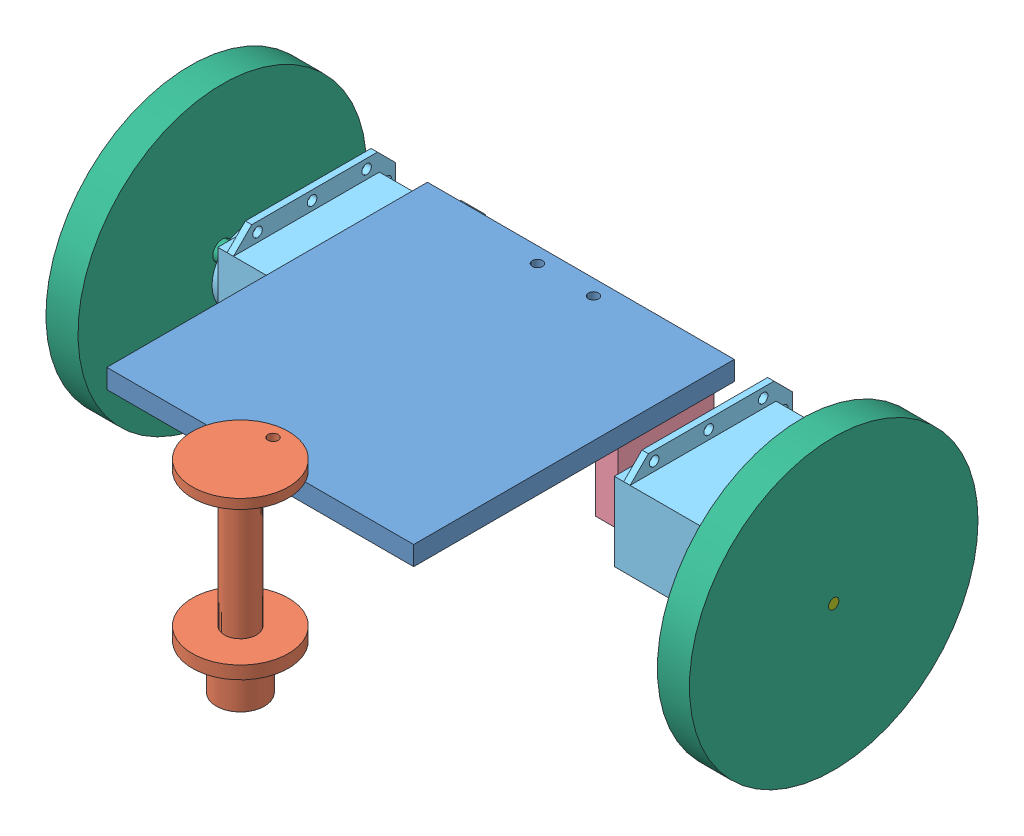
SolidWorks assembly Assem1, configuration Default. Lengths in mm.
Overall size (200.68 111.99 157.99).
10 component instances, 7 part files, 27 mates.
Components (placement in the parent):
- base plate-1: base plate [Default] at origin size (95.7 6 100)
- castor-1: castor [Default] at (0.7825 -41 56.9721) x (-0.997467 0 0.071136) z (-0.071136 0 -0.997467) size (30 63 30)
- castorwheel-1: castorwheel [Default] at (0.7825 -54 56.9721) x (-0.599803 0 0.800148) z (0 1 0) size (13 13 17.5)
- motor clamp-2: motor clamp [Default] x (-1 0 0) z (0 0 1) size (84.11 28 30)
- MX-28-1: MX-28 [Default] at (227.8585 63.0507 -670.7152) x (-1 0 0) z (0 0 1) size (43.48 35.8 50.6)
- MX-28-2: MX-28 [Default] at (-228.8539 -116.0004 -670.7152) size (43.48 35.8 50.6)
- wheel-1: wheel [Default] at (-95.84 -26.3818 -29.0254) x (0 0.286108 0.958197) z (0 -0.958197 0.286108) size (90 14.8 90)
- shaft-1: shaft [Default] at (-93.44 -26.4668 -29) x (0 -1 0) z (0 0 1) size (3.2 16.6 3.2)
- wheel-2: wheel [Default] at (94.8445 -26.4828 -29.0887) x (0 -1 0) z (0 0 1) size (90 14.8 90)
- shaft-2: shaft [Default] at (92.4445 -26.4828 -29) x (0 1 0) z (0 0 1) size (3.2 16.6 3.2)
Mates (geometry in assembly coordinates):
- Coincident3: coincident: plane of base plate-1 through (0 0 0) normal (0 0 1); plane of assembly through (0 0 0) normal (0 0 1)
- Coincident4: coincident: plane of base plate-1 through (0 0 0) normal (0 1 0); plane of assembly through (0 0 0) normal (0 1 0)
- Coincident6: coincident aligned: plane of base plate-1 through (0 0 0) normal (1 0 0); plane of assembly through (0 0 0) normal (1 0 0)
- Coincident7: coincident anti-aligned: plane of base plate-1 through (0 3 0) normal (0 1 0); plane of base plate-1 through (47.85 3 -64) normal (0 -1 0)
- Coincident8: coincident aligned: axis of base plate-1 through (8.75 3 -45.1814) axis (0 -1 0); axis of base plate-1 through (8.75 8 -45.1814) axis (0 -1 0)
- Coincident9: coincident anti-aligned: axis of base plate-1 through (0 3 46) axis (0 -1 0); axis of castor-1 through (0 3 46) axis (0 1 0)
- Coincident10: coincident anti-aligned: plane of base plate-1 through (0 3 0) normal (0 1 0); plane of castor-1 through (0.7825 3 56.9721) normal (0 -1 0)
- Lock1: lock: unknown of base plate-1; unknown of castor-1
- Coincident12: coincident anti-aligned: plane of castor-1 through (0.7825 -43 56.9721) normal (0 -1 0); plane of castorwheel-1 through (0.7825 -43 56.9721) normal (0 1 0)
- Coincident13: coincident anti-aligned: axis of castor-1 through (0.7825 -57 56.9721) axis (0 1 0); axis of castorwheel-1 through (0.7825 -43 56.9721) axis (0 -1 0)
- Coincident14: coincident anti-aligned: plane of base plate-1 through (0 -3 0) normal (0 -1 0); plane of motor clamp-2 through (-47.85 -3 -64) normal (0 1 0)
- Coincident15: coincident anti-aligned: axis of base plate-1 through (-8.75 3 -45.1814) axis (0 -1 0); axis of motor clamp-2 through (-8.75 -8 -45.1814) axis (0 1 0)
- Coincident16: coincident anti-aligned: axis of base plate-1 through (8.75 3 -45.1814) axis (0 -1 0); axis of motor clamp-2 through (8.75 -8 -45.1814) axis (0 1 0)
- Coincident17: coincident anti-aligned: axis of motor clamp-2 through (34.5596 -26.4748 -29) axis (1 0 0); axis of MX-28-1 through (45.3445 -26.4748 -29) axis (-1 0 0)
- Parallel1: parallel aligned: plane of base plate-1 through (0 3 0) normal (0 1 0); plane of MX-28-1 through (43.4445 -14.2828 -62) normal (0 1 0)
- Coincident20: coincident aligned: axis of motor clamp-2 through (-42.555 -26.4748 -29) axis (1 0 0); axis of MX-28-2 through (-46.34 -26.4748 -29) axis (1 0 0)
- Coincident22: coincident anti-aligned: plane of motor clamp-2 through (41.5596 -8 0) normal (1 0 0); plane of MX-28-1 through (41.5596 -26.4748 -29) normal (-1 0 0)
- Coincident23: coincident anti-aligned: plane of motor clamp-2 through (-42.555 -8 0) normal (-1 0 0); plane of MX-28-2 through (-42.555 -26.4748 -29) normal (1 0 0)
- Parallel2: parallel aligned: plane of base plate-1 through (0 3 0) normal (0 1 0); plane of MX-28-2 through (-44.44 -14.2668 -17) normal (0 1 0)
- Coincident25: coincident aligned: axis of MX-28-2 through (-86.04 -26.4668 -29) axis (1 0 0); axis of wheel-1 through (-100.84 -26.4668 -29) axis (1 0 0)
- Coincident26: coincident anti-aligned: axis of wheel-1 through (-100.84 -26.4668 -29) axis (1 0 0); axis of shaft-1 through (-86.04 -26.4668 -29) axis (-1 0 0)
- Coincident27: coincident anti-aligned: plane of MX-28-2 through (-84.24 -26.4668 -29) normal (-1 0 0); plane of shaft-1 through (-84.24 -26.4668 -29) normal (1 0 0)
- Coincident28: coincident aligned: plane of wheel-1 through (-100.84 -26.4668 -29) normal (-1 0 0); plane of shaft-1 through (-100.84 -26.4668 -29) normal (-1 0 0)
- Coincident29: coincident aligned: axis of MX-28-1 through (82.0445 -26.4828 -29) axis (-1 0 0); axis of wheel-2 through (125.6114 -26.4828 -29) axis (-1 0 0)
- Coincident30: coincident anti-aligned: axis of wheel-2 through (99.8445 -26.4828 -29) axis (-1 0 0); axis of shaft-2 through (85.0445 -26.4828 -29) axis (1 0 0)
- Coincident31: coincident aligned: plane of wheel-2 through (99.8445 -26.4828 -29) normal (1 0 0); plane of shaft-2 through (99.8445 -26.4828 -29) normal (1 0 0)
- Coincident32: coincident anti-aligned: plane of MX-28-1 through (83.2445 -26.4828 -29) normal (1 0 0); plane of shaft-2 through (83.2445 -26.4828 -29) normal (-1 0 0)
